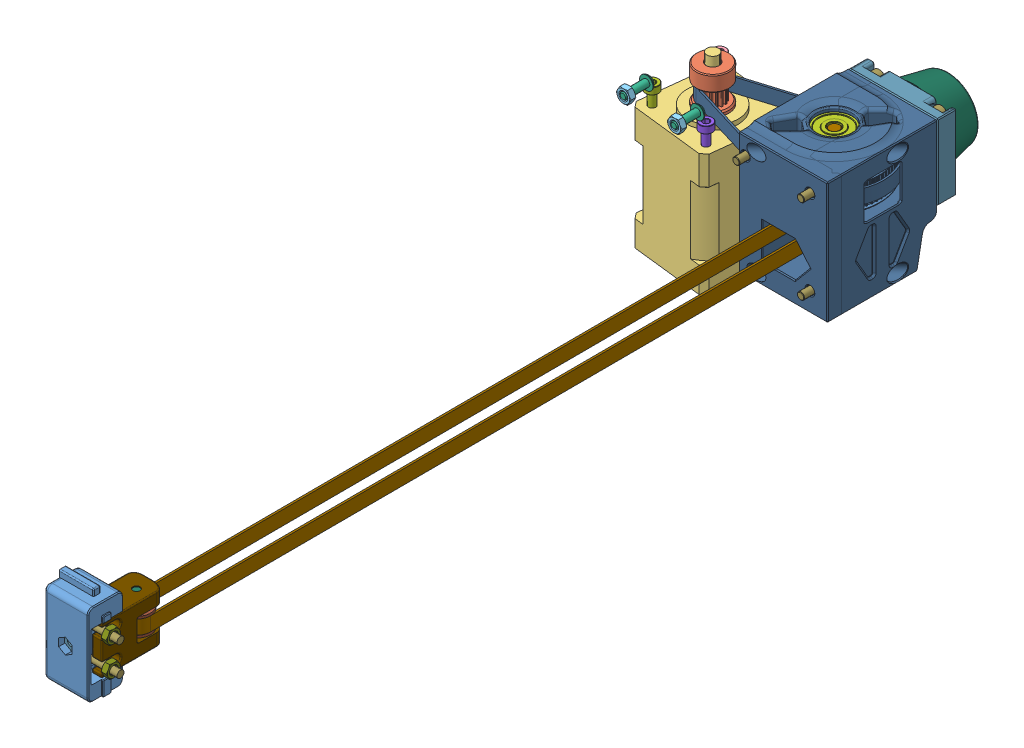
SolidWorks assembly Z-New Z Drive, configuration Z-split. Lengths in mm.
Overall size (130.55 126.29 374.31).
66 component instances, 35 part files, 47 mates.
Components (placement in the parent):
- Shaft Assembly  (1) (1) (2)^Z-New Z Drive-1: Shaft Assembly  (1) (1) (2)^Z-New Z Drive [Default] at (96.6514 -0.1626 -348.8905) x (-0.819152 0 0.573576) z (-0.573576 0 -0.819152) size (88.47 47.67 79.82) (virtual)
  - 64T Front Pulley Gear (1) (2) (2) (1) (1) (1) (1) (1) (1) (2)^Shaft Assembly  (1) (1) (2)_Z-New Z Drive-1: 64T Front Pulley Gear (1) (2) (2) (1) (1) (1) (1) (1) (1) (2)^Shaft Assembly  (1) (1) (2)_Z-New Z Drive [Default] at (105.2338 103.968 -156.4924) x (0.830091 0 0.557627) z (0 1 0) size (53.63 53.63 16) (virtual)
    - 64T Front Pulley Gear (3) (2) (1) (1) (1) (1) (1) (1) (2)^64T Front Pulley Gear (1) (2) (2) (1) (1) (1) (1) (1) (1) (2)_Shaft Assembly  (1) (1) (2)_Z-New Z Drive-1: 64T Front Pulley Gear (3) (2) (1) (1) (1) (1) (1) (1) (2)^64T Front Pulley Gear (1) (2) (2) (1) (1) (1) (1) (1) (1) (2)_Shaft Assembly  (1) (1) (2)_Z-New Z Drive [Default] at (-3.0415 1.9635 -1.417) x (0.383262 0.92364 0) z (0 0 1) size (41.03 41.03 11.2) (virtual)
    - GT2 16T 6mm - Deflanged (4) (2) (1) (1) (1) (1) (1) (1) (2)^64T Front Pulley Gear (1) (2) (2) (1) (1) (1) (1) (1) (1) (2)_Shaft Assembly  (1) (1) (2)_Z-New Z Drive-1: GT2 16T 6mm - Deflanged (4) (2) (1) (1) (1) (1) (1) (1) (2)^64T Front Pulley Gear (1) (2) (2) (1) (1) (1) (1) (1) (1) (2)_Shaft Assembly  (1) (1) (2)_Z-New Z Drive [Default] at (-3.4656 2.1394 -3.0177) x (0 0 1) z (-0.383262 -0.92364 0) size (3 2.5 3) (virtual)
    - GT2 16T 6mm - Deflanged (1) (2) (2) (1) (1) (1) (1) (1) (1) (2)^64T Front Pulley Gear (1) (2) (2) (1) (1) (1) (1) (1) (1) (2)_Shaft Assembly  (1) (1) (2)_Z-New Z Drive-1: GT2 16T 6mm - Deflanged (1) (2) (2) (1) (1) (1) (1) (1) (1) (2)^64T Front Pulley Gear (1) (2) (2) (1) (1) (1) (1) (1) (1) (2)_Shaft Assembly  (1) (1) (2)_Z-New Z Drive [Default] at (-3.2175 1.5395 -3.0177) x (0 0 1) z (-0.383262 -0.92364 0) size (3 3 2.5) (virtual)
    - GT2 16T 6mm - Deflanged (2) (2) (2) (1) (1) (1) (1) (1) (1) (2)^64T Front Pulley Gear (1) (2) (2) (1) (1) (1) (1) (1) (1) (2)_Shaft Assembly  (1) (1) (2)_Z-New Z Drive-1: GT2 16T 6mm - Deflanged (2) (2) (2) (1) (1) (1) (1) (1) (1) (2)^64T Front Pulley Gear (1) (2) (2) (1) (1) (1) (1) (1) (1) (2)_Shaft Assembly  (1) (1) (2)_Z-New Z Drive [Default] at (-3.0415 1.9635 -3.0177) x (0 0 1) z (-0.383262 -0.92364 0) size (16 13.9 13.9) (virtual)
    - socket set screw cup point_am(B18.3.6M - M3 x 0.5 x 6 Hex Socket Type I Cup Pt (2) (2) (1) (1) (1) (1) (1) (1) (2)^64T Front Pulley Gear (1) (2) (2) (1) (1) (1) (1) (1) (1) (2)_Shaft Assembly  ~-2: socket set screw cup point_am(B18.3.6M - M3 x 0.5 x 6 Hex Socket Type I Cup Pt (2) (2) (1) (1) (1) (1) (1) (1) (2)^64T Front Pulley Gear (1) (2) (2) (1) (1) (1) (1) (1) (1) (2)_Shaft Assembly  ~ [Default] at (2.3039 -0.2546 11.4323) x (0 0 -1) z (0.383262 0.92364 0) size (6 14.57 14.57) (virtual)
  - M5x.5mm Washer (1) (1) (1) (1) (1) (1) (2)^Shaft Assembly  (1) (1) (2)_Z-New Z Drive-1: M5x.5mm Washer (1) (1) (1) (1) (1) (1) (2)^Shaft Assembly  (1) (1) (2)_Z-New Z Drive [Default] at (102.988 85.783 -159.6654) x (0.343907 0 -0.939004) z (0 -1 0) size (10 10 0.5) (virtual)
  - 625 2RS (1) (2) (2) (1) (1) (1) (1) (1) (1) (2)^Shaft Assembly  (1) (1) (2)_Z-New Z Drive-1: 625 2RS (1) (2) (2) (1) (1) (1) (1) (1) (1) (2)^Shaft Assembly  (1) (1) (2)_Z-New Z Drive [Default] at (102.988 125.8503 -159.6654) x (0.343907 0 -0.939004) z (-0.939004 0 -0.343907) size (16 5 16) (virtual)
  - 625 2RS (1) (2) (2) (1) (1) (1) (1) (1) (1) (2)^Shaft Assembly  (1) (1) (2)_Z-New Z Drive-2: 625 2RS (1) (2) (2) (1) (1) (1) (1) (1) (1) (2)^Shaft Assembly  (1) (1) (2)_Z-New Z Drive [Default] at (102.988 83.183 -159.6654) x (0.343907 0 -0.939004) z (-0.939004 0 -0.343907) size (16 5 16) (virtual)
  - GT2 16T v2 (1) (1)(Mirror) (1) (2) (2) (1) (1) (1) (1) (1) (1) (2)^Shaft Assembly  (1) (1) (2)_Z-New Z Drive-1: GT2 16T v2 (1) (1)(Mirror) (1) (2) (2) (1) (1) (1) (1) (1) (1) (2)^Shaft Assembly  (1) (1) (2)_Z-New Z Drive [Default] at (102.988 81.783 -159.5044) x (0 1 0) z (0 0 -1) size (15.5 13.9 13.9) (virtual)
  - 5mm shaft (2) (2) (1) (1) (1) (1) (1) (1) (2)^Shaft Assembly  (1) (1) (2)_Z-New Z Drive-1: 5mm shaft (2) (2) (1) (1) (1) (1) (1) (1) (2)^Shaft Assembly  (1) (1) (2)_Z-New Z Drive [Default] at (103.0288 55.45 -154.0231) x (0 1 0) z (0.343907 0 -0.939004) size (47 5 5) (virtual)
  - M5x.5mm Washer (1) (1) (1) (1) (1) (1) (2)^Shaft Assembly  (1) (1) (2)_Z-New Z Drive-2: M5x.5mm Washer (1) (1) (1) (1) (1) (1) (2)^Shaft Assembly  (1) (1) (2)_Z-New Z Drive [Default] at (102.988 85.283 -159.6654) x (0.343907 0 -0.939004) z (0 -1 0) size (10 10 0.5) (virtual)
  - M5x.5mm Washer (1) (1) (1) (1) (1) (1) (2)^Shaft Assembly  (1) (1) (2)_Z-New Z Drive-3: M5x.5mm Washer (1) (1) (1) (1) (1) (1) (2)^Shaft Assembly  (1) (1) (2)_Z-New Z Drive [Default] at (102.988 84.783 -159.6654) x (0.343907 0 -0.939004) z (0 -1 0) size (10 10 0.5) (virtual)
  - GT2-188 Belt Loop (2) (1) (1) (1) (1) (1) (1) (2)^Shaft Assembly  (1) (1) (2)_Z-New Z Drive-1: GT2-188 Belt Loop (2) (1) (1) (1) (1) (1) (1) (2)^Shaft Assembly  (1) (1) (2)_Z-New Z Drive [Default] at (279.3736 0 -229.8195) x (-0.819152 0 -0.573576) z (0.573576 0 -0.819152) size (78.6 6 42) (virtual)
- Z Idler (1) (1) (2)^Z-New Z Drive-1: Z Idler (1) (1) (2)^Z-New Z Drive [Default] at (90.9488 70.5622 -205) x (0 1 0) z (0 0 -1) size (37.74 26.65 33.88) (virtual)
  - Z Idler Hardware (2) (2) (1) (1) (1) (1) (1) (1) (2)^Z Idler (1) (1) (2)_Z-New Z Drive-1: Z Idler Hardware (2) (2) (1) (1) (1) (1) (1) (1) (2)^Z Idler (1) (1) (2)_Z-New Z Drive [Default] at origin size (21.65 26.65 31.38) (virtual)
    - f623_stack (2) (2) (1) (1) (1) (1) (1) (1) (2)^Z Idler Hardware (2) (2) (1) (1) (1) (1) (1) (1) (2)_Z Idler (1) (1) (2)_Z-New Z Drive-1: f623_stack (2) (2) (1) (1) (1) (1) (1) (1) (2)^Z Idler Hardware (2) (2) (1) (1) (1) (1) (1) (1) (2)_Z Idler (1) (1) (2)_Z-New Z Drive [Default] at (41.1064 9.5714 -382.996) x (0 0 -1) z (1 0 0) size (15.29 15.29 8) (virtual)
      - f623-rs (1)(Mirror)(Mirror) (1)(Mirror) (2) (2) (1) (1) (1) (1) (1) (1) (2)^f623_stack (2) (2) (1) (1) (1) (1) (1) (1) (2)_Z Idler Hardware (2) (2) (1) (1) (1) (1) (1) (1) (2)_Z Idler (1) (1) (~-1: f623-rs (1)(Mirror)(Mirror) (1)(Mirror) (2) (2) (1) (1) (1) (1) (1) (1) (2)^f623_stack (2) (2) (1) (1) (1) (1) (1) (1) (2)_Z Idler Hardware (2) (2) (1) (1) (1) (1) (1) (1) (2)_Z Idler (1) (1) (~ [Default] at (-39.1834 4.0141 -21.5494) x (0.923728 0.383049 0) z (0 0 -1) size (11.7 11.7 4) (virtual)
      - f623-rs (1)(Mirror)(Mirror) (1)(Mirror) (2) (2) (1) (1) (1) (1) (1) (1) (2)^f623_stack (2) (2) (1) (1) (1) (1) (1) (1) (2)_Z Idler Hardware (2) (2) (1) (1) (1) (1) (1) (1) (2)_Z Idler (1) (1) (~-2: f623-rs (1)(Mirror)(Mirror) (1)(Mirror) (2) (2) (1) (1) (1) (1) (1) (1) (2)^f623_stack (2) (2) (1) (1) (1) (1) (1) (1) (2)_Z Idler Hardware (2) (2) (1) (1) (1) (1) (1) (1) (2)_Z Idler (1) (1) (~ [Default] at (-39.1834 4.0141 -17.9494) size (11.7 11.7 4) (virtual)
    - M3x25 BHCS (2) (2) (1) (1) (1) (1) (1) (1) (2)^Z Idler Hardware (2) (2) (1) (1) (1) (1) (1) (1) (2)_Z Idler (1) (1) (2)_Z-New Z Drive-1: M3x25 BHCS (2) (2) (1) (1) (1) (1) (1) (1) (2)^Z Idler Hardware (2) (2) (1) (1) (1) (1) (1) (1) (2)_Z Idler (1) (1) (2)_Z-New Z Drive [Default] at (38.0515 -176.8064 -348.5) x (0 1 0) z (-1 0 0) size (26.65 5.7 5.7) (virtual)
    - M3x25 BHCS (2) (2) (1) (1) (1) (1) (1) (1) (2)^Z Idler Hardware (2) (2) (1) (1) (1) (1) (1) (1) (2)_Z Idler (1) (1) (2)_Z-New Z Drive-2: M3x25 BHCS (2) (2) (1) (1) (1) (1) (1) (1) (2)^Z Idler Hardware (2) (2) (1) (1) (1) (1) (1) (1) (2)_Z Idler (1) (1) (2)_Z-New Z Drive [Default] at (50.5295 -176.8064 -348.5) x (0 1 0) z (-1 0 0) size (26.65 5.7 5.7) (virtual)
    - M3x12 SHCS(Mirror) (2) (2) (1) (1) (1) (1) (1) (1) (2)^Z Idler Hardware (2) (2) (1) (1) (1) (1) (1) (1) (2)_Z Idler (1) (1) (2)_Z-New Z Drive-1: M3x12 SHCS(Mirror) (2) (2) (1) (1) (1) (1) (1) (1) (2)^Z Idler Hardware (2) (2) (1) (1) (1) (1) (1) (1) (2)_Z Idler (1) (1) (2)_Z-New Z Drive [Default] at (21.5568 9.4 -350.5435) x (0 0 -1) z (-1 0 0) size (15 5.5 5.5) (virtual)
    - M3_Hex_Nut (1) (2) (2) (1) (1) (1) (1) (1) (1) (2)^Z Idler Hardware (2) (2) (1) (1) (1) (1) (1) (1) (2)_Z Idler (1) (1) (2)_Z-New Z Drive-1: M3_Hex_Nut (1) (2) (2) (1) (1) (1) (1) (1) (1) (2)^Z Idler Hardware (2) (2) (1) (1) (1) (1) (1) (1) (2)_Z Idler (1) (1) (2)_Z-New Z Drive [Default] at origin size (6.58 5.71 2.5) (virtual)
    - M3x25 BHCS  (1)(Mirror) (2) (2) (1) (1) (1) (1) (1) (1) (2)^Z Idler Hardware (2) (2) (1) (1) (1) (1) (1) (1) (2)_Z Idler (1) (1) (2)_Z-New Z Drive-1: M3x25 BHCS  (1)(Mirror) (2) (2) (1) (1) (1) (1) (1) (1) (2)^Z Idler Hardware (2) (2) (1) (1) (1) (1) (1) (1) (2)_Z Idler (1) (1) (2)_Z-New Z Drive [Default] at (-166.1216 -0.5 -366.7934) size (21.65 5.7 5.7) (virtual)
    - M3_Hex_Nut (3) (2) (1) (1) (1) (1) (1) (1) (2)^Z Idler Hardware (2) (2) (1) (1) (1) (1) (1) (1) (2)_Z Idler (1) (1) (2)_Z-New Z Drive-1: M3_Hex_Nut (3) (2) (1) (1) (1) (1) (1) (1) (2)^Z Idler Hardware (2) (2) (1) (1) (1) (1) (1) (1) (2)_Z Idler (1) (1) (2)_Z-New Z Drive [Default] at (27.6598 21.3512 -362.55) x (-1 0 0) z (0 0 1) size (5.5 2.4 6.35) (virtual)
    - M3_Hex_Nut (3) (2) (1) (1) (1) (1) (1) (1) (2)^Z Idler Hardware (2) (2) (1) (1) (1) (1) (1) (1) (2)_Z Idler (1) (1) (2)_Z-New Z Drive-2: M3_Hex_Nut (3) (2) (1) (1) (1) (1) (1) (1) (2)^Z Idler Hardware (2) (2) (1) (1) (1) (1) (1) (1) (2)_Z Idler (1) (1) (2)_Z-New Z Drive [Default] at (15.1818 21.3512 -362.55) x (-1 0 0) z (0 0 1) size (5.5 2.4 6.35) (virtual)
    - m3x.5 spacer (2) (1) (1) (1) (1) (1) (1) (2)^Z Idler Hardware (2) (2) (1) (1) (1) (1) (1) (1) (2)_Z Idler (1) (1) (2)_Z-New Z Drive-1: m3x.5 spacer (2) (1) (1) (1) (1) (1) (1) (2)^Z Idler Hardware (2) (2) (1) (1) (1) (1) (1) (1) (2)_Z Idler (1) (1) (2)_Z-New Z Drive [Default] at (-70.5622 -90.9488 -205) x (0 -1 0) z (0 0 -1) size (7 0.5 7) (virtual)
    - m3x.5 spacer (2) (1) (1) (1) (1) (1) (1) (2)^Z Idler Hardware (2) (2) (1) (1) (1) (1) (1) (1) (2)_Z Idler (1) (1) (2)_Z-New Z Drive-2: m3x.5 spacer (2) (1) (1) (1) (1) (1) (1) (2)^Z Idler Hardware (2) (2) (1) (1) (1) (1) (1) (1) (2)_Z Idler (1) (1) (2)_Z-New Z Drive [Default] at (-79.0622 -90.9488 -205) x (0 -1 0) z (0 0 -1) size (7 0.5 7) (virtual)
  - Z Tensioner (2) (2) (1) (1) (1) (1) (1) (1) (2)^Z Idler (1) (1) (2)_Z-New Z Drive-1: Z Tensioner (2) (2) (1) (1) (1) (1) (1) (1) (2)^Z Idler (1) (1) (2)_Z-New Z Drive [Default] at (-4.8272 -36.0072 -7.524) size (20.5 13.43 27.03) (virtual)
  - Z Idler (1) (1) (2)-43^Z Idler (1) (1) (2)_Z-New Z Drive-1: Z Idler (1) (1) (2)-43^Z Idler (1) (1) (2)_Z-New Z Drive [Default] at origin size (37.74 19.4 15) (virtual)
- Z Motor (1) (1) (2)^Z-New Z Drive-1: Z Motor (1) (1) (2)^Z-New Z Drive [Default] at (-4.232 0 0) size (38.47 73.89 46.71) (virtual)
  - NEMA14 Stepper  (2) (2) (1) (1) (1) (1) (1) (1) (2)^Z Motor (1) (1) (2)_Z-New Z Drive-1: NEMA14 Stepper  (2) (2) (1) (1) (1) (1) (1) (1) (2)^Z Motor (1) (1) (2)_Z-New Z Drive [Default] at (74.4075 59.0804 -141.0739) x (0 0 1) z (-1 0 0) size (38.47 73.89 38.47) (virtual)
    - GT2 16T (2) (2) (1) (1) (1) (1) (1) (1) (2)^NEMA14 Stepper  (2) (2) (1) (1) (1) (1) (1) (1) (2)_Z Motor (1) (1) (2)_Z-New Z Drive-1: GT2 16T (2) (2) (1) (1) (1) (1) (1) (1) (2)^NEMA14 Stepper  (2) (2) (1) (1) (1) (1) (1) (1) (2)_Z Motor (1) (1) (2)_Z-New Z Drive [Default] at (-96.0075 -200.8988 -75.6556) x (0.343907 -0.939004 0) z (0 0 -1) size (19.21 18.26 13.9) (virtual)
    - NEMA14 Stepper  (2) (2) (1) (1) (1) (1) (1) (1) (2)-44^NEMA14 Stepper  (2) (2) (1) (1) (1) (1) (1) (1) (2)_Z Motor (1) (1) (2)_Z-New Z Drive-1: NEMA14 Stepper  (2) (2) (1) (1) (1) (1) (1) (1) (2)-44^NEMA14 Stepper  (2) (2) (1) (1) (1) (1) (1) (1) (2)_Z Motor (1) (1) (2)_Z-New Z Drive [Default] at origin size (38.47 73.29 38.47) (virtual)
  - Hardware (2) (2) (1) (1) (1) (1) (1) (1) (2)^Z Motor (1) (1) (2)_Z-New Z Drive-1: Hardware (2) (2) (1) (1) (1) (1) (1) (1) (2)^Z Motor (1) (1) (2)_Z-New Z Drive [Default] at (-1.75 0 0) size (31.39 22.35 44.61) (virtual)
    - M3x12 SHCS v1 (2) (2) (1) (1) (1) (1) (3) (1) (2)^Hardware (2) (2) (1) (1) (1) (1) (1) (1) (2)_Z Motor (1) (1) (2)_Z-New Z Drive-1: M3x12 SHCS v1 (2) (2) (1) (1) (1) (1) (3) (1) (2)^Hardware (2) (2) (1) (1) (1) (1) (1) (1) (2)_Z Motor (1) (1) (2)_Z-New Z Drive [Default] at (45.7271 67.583 -171.9687) x (-1 0 0) z (0 -1 0) size (5.5 5.5 15) (virtual)
    - M3_Hex_Nut v1 (5) (2) (1) (1) (1) (1) (1) (1) (1) (2)^Hardware (2) (2) (1) (1) (1) (1) (1) (1) (2)_Z Motor (1) (1) (2)_Z-New Z Drive-1: M3_Hex_Nut v1 (5) (2) (1) (1) (1) (1) (1) (1) (1) (2)^Hardware (2) (2) (1) (1) (1) (1) (1) (1) (2)_Z Motor (1) (1) (2)_Z-New Z Drive [Default] at (69.1922 117.083 -132.6999) x (0 1 0) z (1 0 0) size (5.5 2.4 6.35) (virtual)
    - M3_Hex_Nut v1 (5) (2) (1) (1) (1) (1) (1) (1) (1) (2)^Hardware (2) (2) (1) (1) (1) (1) (1) (1) (2)_Z Motor (1) (1) (2)_Z-New Z Drive-2: M3_Hex_Nut v1 (5) (2) (1) (1) (1) (1) (1) (1) (1) (2)^Hardware (2) (2) (1) (1) (1) (1) (1) (1) (2)_Z Motor (1) (1) (2)_Z-New Z Drive [Default] at (47.4922 117.083 -132.6999) x (0 1 0) z (1 0 0) size (5.5 2.4 6.35) (virtual)
    - M3x10 BHCS v2 (2) (1) (1) (1) (1) (1) (1) (2)^Hardware (2) (2) (1) (1) (1) (1) (1) (1) (2)_Z Motor (1) (1) (2)_Z-New Z Drive-1: M3x10 BHCS v2 (2) (1) (1) (1) (1) (1) (1) (2)^Hardware (2) (2) (1) (1) (1) (1) (1) (1) (2)_Z Motor (1) (1) (2)_Z-New Z Drive [Default] at (69.1922 117.083 -142.9419) x (0 -1 0) z (0 0 -1) size (5.7 5.7 11.65) (virtual)
    - M3x10 BHCS v2 (2) (1) (1) (1) (1) (1) (1) (2)^Hardware (2) (2) (1) (1) (1) (1) (1) (1) (2)_Z Motor (1) (1) (2)_Z-New Z Drive-2: M3x10 BHCS v2 (2) (1) (1) (1) (1) (1) (1) (2)^Hardware (2) (2) (1) (1) (1) (1) (1) (1) (2)_Z Motor (1) (1) (2)_Z-New Z Drive [Default] at (47.4922 117.083 -142.9419) x (0 -1 0) z (0 0 -1) size (5.7 5.7 11.65) (virtual)
    - M3x12 SHCS v1 (2) (2) (1) (1) (1) (1) (1) (1) (1) (2)^Hardware (2) (2) (1) (1) (1) (1) (1) (1) (2)_Z Motor (1) (1) (2)_Z-New Z Drive-1: M3x12 SHCS v1 (2) (2) (1) (1) (1) (1) (1) (1) (1) (2)^Hardware (2) (2) (1) (1) (1) (1) (1) (1) (2)_Z Motor (1) (1) (2)_Z-New Z Drive [Default] at (44.9681 67.583 -145.9798) x (-1 0 0) z (0 -1 0) size (5.5 5.5 15) (virtual)
    - M3x12 SHCS v1 (2) (2) (1) (1) (1) (1) (2) (1) (1) (2)^Hardware (2) (2) (1) (1) (1) (1) (1) (1) (2)_Z Motor (1) (1) (2)_Z-New Z Drive-1: M3x12 SHCS v1 (2) (2) (1) (1) (1) (1) (2) (1) (1) (2)^Hardware (2) (2) (1) (1) (1) (1) (1) (1) (2)_Z Motor (1) (1) (2)_Z-New Z Drive [Default] at (70.9573 67.583 -145.2311) x (-1 0 0) z (0 -1 0) size (5.5 5.5 15) (virtual)
- Z-Belt (1) (1) (2)^Z-New Z Drive-1: Z-Belt (1) (1) (2)^Z-New Z Drive [Default] at (-0.681 -0.2657 26.2585) x (-0.999996 0 0.00269) z (0.00269 0 0.999996) size (11.65 6 309.55) (virtual)
- NewZDrive^Z-New Z Drive-1: NewZDrive^Z-New Z Drive [Default] at origin size (130.55 126.29 141.33) (virtual)
- M3 Threaded Insert Short^Z-New Z Drive-1: M3 Threaded Insert Short^Z-New Z Drive [Default] at (89.1744 121.8496 -159.1836) x (0.638323 0.430218 0.638323) z (0.30421 -0.902725 0.30421) size (5.56 3.8 5.56) (virtual)
- M3 Threaded Insert Short^Z-New Z Drive-6: M3 Threaded Insert Short^Z-New Z Drive [Default] at (89.1744 77.5996 -159.1836) x (0.649438 0.39555 0.649438) z (0.279696 -0.918444 0.279696) size (5.56 3.8 5.56) (virtual)
- M3 Threaded Insert Short^Z-New Z Drive-7: M3 Threaded Insert Short^Z-New Z Drive [Default] at (119.6898 121.476 -181.8577) x (-0.999908 0.013571 0) z (-0.013571 -0.999908 0) size (5.56 3.8 5.56) (virtual)
- M3 Threaded Insert Short^Z-New Z Drive-8: M3 Threaded Insert Short^Z-New Z Drive [Default] at (93.2706 121.476 -181.8577) x (-0.989411 -0.145138 0) z (0.145138 -0.989411 0) size (5.56 3.8 5.56) (virtual)
- M3 Threaded Insert Short^Z-New Z Drive-9: M3 Threaded Insert Short^Z-New Z Drive [Default] at (93.2706 96.3627 -181.8577) x (-0.962877 -0.269941 0) z (0.269941 -0.962877 0) size (5.56 3.8 5.56) (virtual)
- M3x6 SHCS^Z-New Z Drive-1: M3x6 SHCS^Z-New Z Drive [Default] at (90 117.4996 -97.011) x (0.89523 -0.445605 0) z (0 0 -1) size (5.5 5.5 9) (virtual)
- M3x6 SHCS^Z-New Z Drive-2: M3x6 SHCS^Z-New Z Drive [Default] at (117.5 117.4996 -97.011) x (0.954557 -0.298027 0) z (0 0 -1) size (5.5 5.5 9) (virtual)
- M3x6 SHCS^Z-New Z Drive-3: M3x6 SHCS^Z-New Z Drive [Default] at (117.5 81.4996 -97.011) x (0.984736 -0.174055 0) z (0 0 -1) size (5.5 5.5 9) (virtual)
- M3x6 SHCS^Z-New Z Drive-5: M3x6 SHCS^Z-New Z Drive [Default] at (119.6898 121.476 -145.8577) x (-0.083964 -0.996469 0) z (0 0 -1) size (5.5 5.5 9) (virtual)
- M3x6 SHCS^Z-New Z Drive-7: M3x6 SHCS^Z-New Z Drive [Default] at (93.2706 121.476 -145.8577) x (0.999876 -0.015721 0) z (0 0 -1) size (5.5 5.5 9) (virtual)
- M3x6 SHCS^Z-New Z Drive-9: M3x6 SHCS^Z-New Z Drive [Default] at (93.2706 96.3627 -145.8577) x (-0.419713 -0.907657 0) z (0 0 -1) size (5.5 5.5 9) (virtual)
- M3 Threaded Insert Short^Z-New Z Drive-11: M3 Threaded Insert Short^Z-New Z Drive [Default] at (96.8747 121.1496 -137.1854) x (0.634686 0.440849 0.634686) z (0.311727 -0.897581 0.311727) size (5.56 3.8 5.56) (virtual)
- M3 Threaded Insert Short^Z-New Z Drive-13: M3 Threaded Insert Short^Z-New Z Drive [Default] at (96.8747 76.8996 -137.1854) x (0.631673 0.44942 0.631673) z (0.317788 -0.893321 0.317788) size (5.56 3.8 5.56) (virtual)
- M3x25 SHCS^Z-New Z Drive-1: M3x25 SHCS^Z-New Z Drive [Default] at (86.1266 121.1496 -126.4374) x (0.273403 -0.922226 0.273403) z (0.707107 0 -0.707107) size (5.5 5.5 28) (virtual)
- M3x25 SHCS^Z-New Z Drive-2: M3x25 SHCS^Z-New Z Drive [Default] at (86.1266 76.8996 -126.4374) x (0.298736 -0.906374 0.298736) z (0.707107 0 -0.707107) size (5.5 5.5 28) (virtual)
- M3x25 SHCS^Z-New Z Drive-4: M3x25 SHCS^Z-New Z Drive [Default] at (77.4541 121.8496 -147.4633) x (0.323611 -0.88913 0.323611) z (0.707107 0 -0.707107) size (5.5 5.5 28) (virtual)
- M3x25 SHCS^Z-New Z Drive-6: M3x25 SHCS^Z-New Z Drive [Default] at (77.4541 77.5996 -147.4633) x (0.347989 -0.870521 0.347989) z (0.707107 0 -0.707107) size (5.5 5.5 28) (virtual)
- ZDriveFootPlate^Z-New Z Drive-1: ZDriveFootPlate^Z-New Z Drive [Default] at (1.792 -1.417 0) size (38.29 31.99 8) (virtual)
- Copy of MISUMI C-30-RK-3215 Foot v1 (2) (1)^Z-New Z Drive-1: Copy of MISUMI C-30-RK-3215 Foot v1 (2) (1)^Z-New Z Drive [Default] at (6741.7678 -8809.5749 -189.8577) x (0 -1 0) z (0 0 -1) size (32 32 15.01) (virtual)
- Copy of M5x16 BHCS  (2) (1)^Z-New Z Drive-1: Copy of M5x16 BHCS  (2) (1)^Z-New Z Drive [Default] at (106.7519 109.0295 -155.6077) x (0 0 1) z (0 -1 0) size (18.75 9.5 9.5) (virtual)
- Copy of Z Drive Hardware (2) (1)-43^Z-New Z Drive-1: Copy of Z Drive Hardware (2) (1)-43^Z-New Z Drive [Default] at (1.792 -1.417 0) size (10.39 9 4) (virtual)
Mates (geometry in assembly coordinates):
- Coincident1: coincident anti-aligned: plane of NewZDrive^Z-New Z Drive-1 through (91.8614 121.8496 -161.8706) normal (-0.707107 0 0.707107); plane of M3 Threaded Insert Short^Z-New Z Drive-1 through (91.8614 121.8496 -161.8706) normal (0.707107 0 -0.707107)
- Concentric1: concentric aligned: cylinder of NewZDrive^Z-New Z Drive-1 through (76.0008 121.8496 -146.01) axis (0.707107 0 -0.707107) radius 2.35; cylinder of M3 Threaded Insert Short^Z-New Z Drive-1 through (91.8614 121.8496 -161.8706) axis (0.707107 0 -0.707107) radius 1.5
- Coincident4: coincident anti-aligned: plane of NewZDrive^Z-New Z Drive-1 through (91.8614 77.5996 -161.8706) normal (-0.707107 0 0.707107); plane of M3 Threaded Insert Short^Z-New Z Drive-6 through (91.8614 77.5996 -161.8706) normal (0.707107 0 -0.707107)
- Concentric4: concentric aligned: cylinder of NewZDrive^Z-New Z Drive-1 through (76.0008 77.5996 -146.01) axis (0.707107 0 -0.707107) radius 2.35; cylinder of M3 Threaded Insert Short^Z-New Z Drive-6 through (91.8614 77.5996 -161.8706) axis (0.707107 0 -0.707107) radius 1.5
- Coincident5: coincident aligned: plane of NewZDrive^Z-New Z Drive-1 through (0 0 -181.8577) normal (0 0 -1); plane of M3 Threaded Insert Short^Z-New Z Drive-7 through (119.6898 121.476 -181.8577) normal (0 0 -1)
- Concentric5: concentric anti-aligned: cylinder of NewZDrive^Z-New Z Drive-1 through (119.6898 121.476 -177.6077) axis (0 0 -1) radius 2.35; cylinder of M3 Threaded Insert Short^Z-New Z Drive-7 through (119.6898 121.476 -178.0577) axis (0 0 1) radius 1.5
- Coincident6: coincident aligned: plane of NewZDrive^Z-New Z Drive-1 through (0 0 -181.8577) normal (0 0 -1); plane of M3 Threaded Insert Short^Z-New Z Drive-8 through (93.2706 121.476 -181.8577) normal (0 0 -1)
- Concentric6: concentric anti-aligned: cylinder of NewZDrive^Z-New Z Drive-1 through (93.2706 121.476 -177.6077) axis (0 0 -1) radius 2.35; cylinder of M3 Threaded Insert Short^Z-New Z Drive-8 through (93.2706 121.476 -178.0577) axis (0 0 1) radius 1.5
- Coincident7: coincident aligned: plane of NewZDrive^Z-New Z Drive-1 through (0 0 -181.8577) normal (0 0 -1); plane of M3 Threaded Insert Short^Z-New Z Drive-9 through (93.2706 96.3627 -181.8577) normal (0 0 -1)
- Concentric7: concentric anti-aligned: cylinder of NewZDrive^Z-New Z Drive-1 through (93.2706 96.3627 -177.6077) axis (0 0 -1) radius 2.35; cylinder of M3 Threaded Insert Short^Z-New Z Drive-9 through (93.2706 96.3627 -178.0577) axis (0 0 1) radius 1.5
- Concentric8: concentric anti-aligned: cylinder of NewZDrive^Z-New Z Drive-1 through (90 117.4996 -181.858) axis (0 0 1) radius 1.7; cylinder of M3x6 SHCS^Z-New Z Drive-1 through (90 117.4996 -137.011) axis (0 0 -1) radius 1.5
- Coincident10: coincident anti-aligned: plane of NewZDrive^Z-New Z Drive-1 through (90 117.4996 -137.011) normal (0 0 -1); plane of M3x6 SHCS^Z-New Z Drive-1 through (90 117.4996 -137.011) normal (0 0 1)
- Concentric9: concentric anti-aligned: cylinder of NewZDrive^Z-New Z Drive-1 through (117.5 117.4996 -181.858) axis (0 0 1) radius 1.7; cylinder of M3x6 SHCS^Z-New Z Drive-2 through (117.5 117.4996 -137.011) axis (0 0 -1) radius 1.5
- Coincident11: coincident anti-aligned: plane of NewZDrive^Z-New Z Drive-1 through (90 117.4996 -137.011) normal (0 0 -1); plane of M3x6 SHCS^Z-New Z Drive-2 through (117.5 117.4996 -137.011) normal (0 0 1)
- Coincident12: coincident anti-aligned: plane of NewZDrive^Z-New Z Drive-1 through (90 117.4996 -137.011) normal (0 0 -1); plane of M3x6 SHCS^Z-New Z Drive-3 through (117.5 81.4996 -137.011) normal (0 0 1)
- Concentric10: concentric anti-aligned: cylinder of NewZDrive^Z-New Z Drive-1 through (117.5 81.4996 -181.858) axis (0 0 1) radius 1.7; cylinder of M3x6 SHCS^Z-New Z Drive-3 through (117.5 81.4996 -137.011) axis (0 0 -1) radius 1.5
- Coincident29: coincident anti-aligned: plane of NewZDrive^Z-New Z Drive-1 through (99.5617 121.1496 -139.8724) normal (-0.707107 0 0.707107); plane of M3 Threaded Insert Short^Z-New Z Drive-11 through (99.5617 121.1496 -139.8724) normal (0.707107 0 -0.707107)
- Concentric24: concentric anti-aligned: cylinder of NewZDrive^Z-New Z Drive-1 through (133.2737 121.1496 -173.5845) axis (-0.707107 0 0.707107) radius 1.7; cylinder of M3 Threaded Insert Short^Z-New Z Drive-11 through (99.5617 121.1496 -139.8724) axis (0.707107 0 -0.707107) radius 1.5
- Coincident30: coincident anti-aligned: plane of NewZDrive^Z-New Z Drive-1 through (99.5617 76.8996 -139.8724) normal (-0.707107 0 0.707107); plane of M3 Threaded Insert Short^Z-New Z Drive-13 through (99.5617 76.8996 -139.8724) normal (0.707107 0 -0.707107)
- Concentric25: concentric anti-aligned: cylinder of NewZDrive^Z-New Z Drive-1 through (133.2737 76.8996 -173.5845) axis (-0.707107 0 0.707107) radius 1.7; cylinder of M3 Threaded Insert Short^Z-New Z Drive-13 through (99.5617 76.8996 -139.8724) axis (0.707107 0 -0.707107) radius 1.5
- Coincident38: coincident anti-aligned: plane of NewZDrive^Z-New Z Drive-1 through (114.4109 121.1496 -154.7216) normal (0.707107 0 -0.707107); plane of M3x25 SHCS^Z-New Z Drive-1 through (114.4109 121.1496 -154.7216) normal (-0.707107 0 0.707107)
- Concentric30: concentric anti-aligned: cylinder of NewZDrive^Z-New Z Drive-1 through (133.2737 121.1496 -173.5845) axis (-0.707107 0 0.707107) radius 1.7; cylinder of M3x25 SHCS^Z-New Z Drive-1 through (114.4109 121.1496 -154.7216) axis (0.707107 0 -0.707107) radius 1.5
- Coincident39: coincident anti-aligned: plane of NewZDrive^Z-New Z Drive-1 through (114.4109 76.8996 -154.7216) normal (0.707107 0 -0.707107); plane of M3x25 SHCS^Z-New Z Drive-2 through (114.4109 76.8996 -154.7216) normal (-0.707107 0 0.707107)
- Concentric31: concentric anti-aligned: cylinder of NewZDrive^Z-New Z Drive-1 through (133.2737 76.8996 -173.5845) axis (-0.707107 0 0.707107) radius 1.7; cylinder of M3x25 SHCS^Z-New Z Drive-2 through (114.4109 76.8996 -154.7216) axis (0.707107 0 -0.707107) radius 1.5
- Coincident49: coincident anti-aligned: plane of NewZDrive^Z-New Z Drive-1 through (105.7383 121.8496 -175.7475) normal (0.707107 0 -0.707107); plane of M3x25 SHCS^Z-New Z Drive-4 through (105.7383 121.8496 -175.7475) normal (-0.707107 0 0.707107)
- Concentric41: concentric anti-aligned: cylinder of NewZDrive^Z-New Z Drive-1 through (118.4245 121.8496 -188.4337) axis (-0.707107 0 0.707107) radius 1.7; cylinder of M3x25 SHCS^Z-New Z Drive-4 through (105.7383 121.8496 -175.7475) axis (0.707107 0 -0.707107) radius 1.5
- Concentric43: concentric anti-aligned: cylinder of Shaft Assembly  (1) (1) (2)^Z-New Z Drive-1/GT2 16T v2 (1) (1)(Mirror) (1) (2) (2) (1) (1) (1) (1) (1) (1) (2)^Shaft Assembly  (1) (1) (2)_Z-New Z Drive-1 through (103.7765 81.6205 -159.1607) axis (0 -1 0) radius 4.84; cylinder of Z-Belt (1) (1) (2)^Z-New Z Drive-1 through (103.7765 88.5353 -159.1607) axis (0 1 0) radius 5.7625
- Concentric45: concentric aligned: cylinder of Z Idler (1) (1) (2)^Z-New Z Drive-1/Z Idler Hardware (2) (2) (1) (1) (1) (1) (1) (1) (2)^Z Idler (1) (1) (2)_Z-New Z Drive-1/f623_stack (2) (2) (1) (1) (1) (1) (1) (1) (2)^Z Idler Hardware (2) (2) (1) (1) (1) (1) (1) (1) (2)_Z Idler (1) (1) (2)_Z-New Z Drive-1/f623-rs (1)(Mirror)(Mirror) (1)(Mirror) (2) (2) (1) (1) (1) (1) (1) (1) (2)^f623_stack (2) (2) (1) (1) (1) (1) (1) (1) (2)_Z Idler Hardware (2) (2) (1) (1) (1) (1) (1) (1) (2)_Z Idler (1) (1) (~-1 through (104.5343 92.1191 138.8126) axis (0 -1 0) radius 5; cylinder of Z-Belt (1) (1) (2)^Z-New Z Drive-1 through (104.5343 88.9191 138.8126) axis (0 -1 0) radius 5.8173
- Coincident51: coincident anti-aligned: plane of Z Idler (1) (1) (2)^Z-New Z Drive-1/Z Idler Hardware (2) (2) (1) (1) (1) (1) (1) (1) (2)^Z Idler (1) (1) (2)_Z-New Z Drive-1/f623_stack (2) (2) (1) (1) (1) (1) (1) (1) (2)^Z Idler Hardware (2) (2) (1) (1) (1) (1) (1) (1) (2)_Z Idler (1) (1) (2)_Z-New Z Drive-1/f623-rs (1)(Mirror)(Mirror) (1)(Mirror) (2) (2) (1) (1) (1) (1) (1) (1) (2)^f623_stack (2) (2) (1) (1) (1) (1) (1) (1) (2)_Z Idler Hardware (2) (2) (1) (1) (1) (1) (1) (1) (2)_Z Idler (1) (1) (~-2 through (108.0041 94.9191 138.8126) normal (0 -1 0); plane of Z-Belt (1) (1) (2)^Z-New Z Drive-1 through (99.0529 94.9191 108.7212) normal (0 1 0)
- Concentric53: concentric aligned: cylinder of NewZDrive^Z-New Z Drive-1 through (119.6898 121.476 -173.8577) axis (0 0 -1) radius 1.7; cylinder of ZDriveFootPlate^Z-New Z Drive-1 through (119.6898 121.476 -181.8577) axis (0 0 -1) radius 1.7
- Concentric54: concentric aligned: cylinder of NewZDrive^Z-New Z Drive-1 through (93.2706 121.476 -173.8577) axis (0 0 -1) radius 1.7; cylinder of ZDriveFootPlate^Z-New Z Drive-1 through (93.2706 121.476 -181.8577) axis (0 0 -1) radius 1.7
- Coincident56: coincident anti-aligned: plane of NewZDrive^Z-New Z Drive-1 through (0 0 -181.8577) normal (0 0 -1); plane of ZDriveFootPlate^Z-New Z Drive-1 through (115.2989 109.005 -181.8577) normal (0 0 1)
- Concentric55: concentric aligned: cylinder of M3x6 SHCS^Z-New Z Drive-5 through (119.6898 121.476 -185.8577) axis (0 0 -1) radius 1.5; cylinder of ZDriveFootPlate^Z-New Z Drive-1 through (119.6898 121.476 -181.8577) axis (0 0 -1) radius 1.7
- Coincident57: coincident anti-aligned: plane of M3x6 SHCS^Z-New Z Drive-5 through (119.6898 121.476 -185.8577) normal (0 0 1); plane of ZDriveFootPlate^Z-New Z Drive-1 through (119.6898 121.7376 -185.8577) normal (0 0 -1)
- Concentric56: concentric aligned: cylinder of M3x6 SHCS^Z-New Z Drive-7 through (93.2706 121.476 -185.8577) axis (0 0 -1) radius 1.5; cylinder of ZDriveFootPlate^Z-New Z Drive-1 through (93.2706 121.476 -181.8577) axis (0 0 -1) radius 1.7
- Coincident58: coincident anti-aligned: plane of M3x6 SHCS^Z-New Z Drive-7 through (93.2706 121.476 -185.8577) normal (0 0 1); plane of ZDriveFootPlate^Z-New Z Drive-1 through (93.2706 121.476 -185.8577) normal (0 0 -1)
- Concentric57: concentric aligned: cylinder of M3x6 SHCS^Z-New Z Drive-9 through (93.2706 96.3627 -185.8577) axis (0 0 -1) radius 1.5; cylinder of ZDriveFootPlate^Z-New Z Drive-1 through (93.2706 96.3627 -181.8577) axis (0 0 -1) radius 1.7
- Coincident59: coincident anti-aligned: plane of M3x6 SHCS^Z-New Z Drive-9 through (93.2706 96.3627 -185.8577) normal (0 0 1); plane of ZDriveFootPlate^Z-New Z Drive-1 through (93.2706 96.3627 -185.8577) normal (0 0 -1)
- Concentric58: concentric anti-aligned: cylinder of NewZDrive^Z-New Z Drive-1 through (118.4245 77.5996 -188.4337) axis (-0.707107 0 0.707107) radius 1.7; cylinder of M3x25 SHCS^Z-New Z Drive-6 through (105.7383 77.5996 -175.7475) axis (0.707107 0 -0.707107) radius 1.5
- Coincident60: coincident anti-aligned: plane of NewZDrive^Z-New Z Drive-1 through (105.7383 77.5996 -175.7475) normal (0.707107 0 -0.707107); plane of M3x25 SHCS^Z-New Z Drive-6 through (105.7383 77.5996 -175.7475) normal (-0.707107 0 0.707107)
- Concentric59: concentric anti-aligned: cylinder of Copy of MISUMI C-30-RK-3215 Foot v1 (2) (1)^Z-New Z Drive-1 through (106.7519 109.0295 -189.8577) axis (0 0 -1) radius 2.5; cylinder of Copy of M5x16 BHCS  (2) (1)^Z-New Z Drive-1 through (106.7519 109.0295 -202.6077) axis (0 0 1) radius 2.5
- Coincident61: coincident anti-aligned: plane of Copy of MISUMI C-30-RK-3215 Foot v1 (2) (1)^Z-New Z Drive-1 through (106.7519 109.0295 -199.8577) normal (0 0 -1); plane of Copy of M5x16 BHCS  (2) (1)^Z-New Z Drive-1 through (104.2519 109.0295 -199.8577) normal (0 0 1)
- Concentric60: concentric aligned: cylinder of ZDriveFootPlate^Z-New Z Drive-1 through (106.7519 109.0295 -185.8577) axis (0 0 1) radius 2.7; cylinder of Copy of M5x16 BHCS  (2) (1)^Z-New Z Drive-1 through (106.7519 109.0295 -202.6077) axis (0 0 1) radius 2.5
- Concentric61: concentric anti-aligned: cylinder of Copy of M5x16 BHCS  (2) (1)^Z-New Z Drive-1 through (106.7519 109.0295 -202.6077) axis (0 0 1) radius 2.5; cylinder of Copy of Z Drive Hardware (2) (1)-43^Z-New Z Drive-1 through (106.7519 109.0295 -185.8577) axis (0 0 -1) radius 2.5
- Coincident62: coincident anti-aligned: plane of ZDriveFootPlate^Z-New Z Drive-1 through (111.948 109.0295 -185.8577) normal (-0.866025 0.5 0); plane of Copy of Z Drive Hardware (2) (1)-43^Z-New Z Drive-1 through (111.948 109.0295 -185.8577) normal (0.866025 -0.5 0)
- Coincident63: coincident: line of ZDriveFootPlate^Z-New Z Drive-1 through (104.1538 113.5295 -185.8577) axis (0 -1 0); plane of Copy of Z Drive Hardware (2) (1)-43^Z-New Z Drive-1 through (107.6452 109.5264 -185.8577) normal (0 0 -1)
- Coincident64: coincident anti-aligned: plane of ZDriveFootPlate^Z-New Z Drive-1 through (115.2989 109.005 -189.8577) normal (0 0 -1); plane of Copy of MISUMI C-30-RK-3215 Foot v1 (2) (1)^Z-New Z Drive-1 through (106.7519 109.0295 -189.8577) normal (0 0 1)
